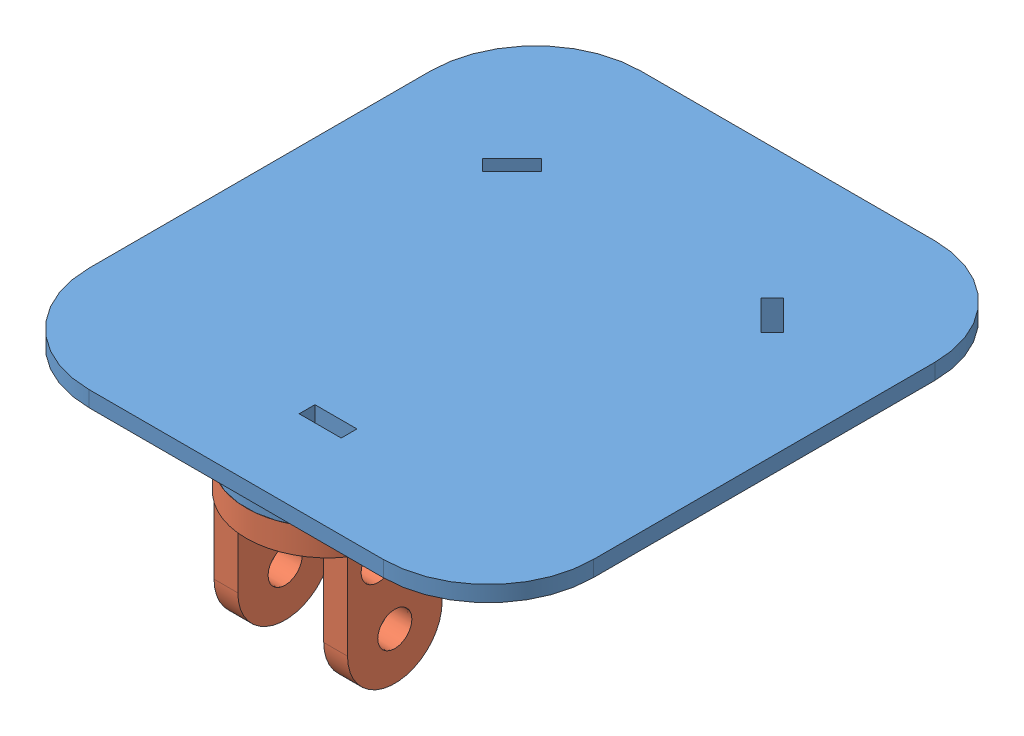
SolidWorks assembly Assem3, configuration Default. Lengths in mm.
Overall size (96 36.85 105).
2 component instances, 2 part files, 3 mates.
Components (placement in the parent):
- w_t4-1: w_t4 [Default] at (14.4054 43.8155 -3.3323) size (96 6.5 105)
- f_k1-1: f_k1 [Default] at (-11.1089 -30.415 44.8111) x (-1 0 0) z (0 0 1) size (25.4 30.39 31.13)
Mates (geometry in assembly coordinates):
- Coincident1: coincident: plane of w_t4-1 through (14.4054 -9.0627 -3.3323) normal (0 -1 0); plane of f_k1-1 through (-11.1089 -9.0627 44.8111) normal (0 1 0)
- Coincident2: coincident: plane of w_t4-1 through (-23.8089 -9.0627 -3.3323) normal (-1 0 0); plane of f_k1-1 through (-23.8089 -30.415 44.8111) normal (-1 0 0)
- Concentric1: concentric aligned: cylinder of w_t4-1 through (-11.1089 -9.0627 44.8111) axis (0 1 0) radius 15.5657; cylinder of f_k1-1 through (-11.1089 -39.415 44.8111) axis (0 1 0) radius 15.5657
